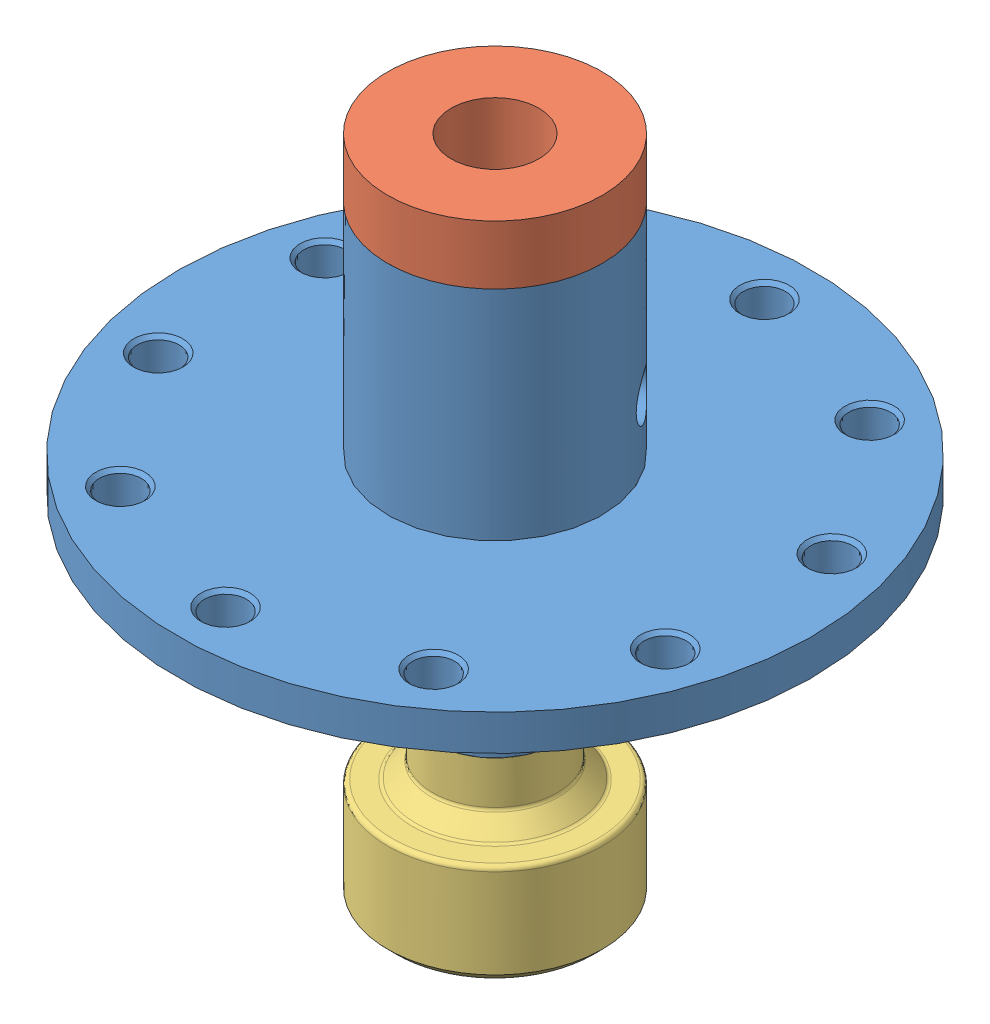
SolidWorks assembly 000012_R05_ASI_ASSEM, configuration Default. Lengths in mm.
Overall size (125.84 94.24 125.84).
3 component instances, 3 part files, 6 mates.
Components (placement in the parent):
- 000011-R07_ASI_TOP-1: 000011-R07_ASI_TOP [Default] x (0.583403 0 0.812183) z (-0.812183 0 0.583403) size (90.17 69.83 90.17)
- 000010-R02_ASI-1: 000010-R02_ASI [Default] at (0 25.4 0) x (-0.830204 0 0.55746) z (-0.55746 0 -0.830204) size (30.48 19.05 30.48)
- 000011-R04_ASI_BOTTOM-1: 000011-R04_ASI_BOTTOM [Default] at (0 -33.766 0) x (0.929472 0 0.368892) z (-0.368892 0 0.929472) size (30.48 23.65 30.48)
Mates (geometry in assembly coordinates):
- Concentric7: concentric aligned: circle of 000011-R07_ASI_TOP-1; line of assembly
- Coincident13: coincident: plane of 000011-R07_ASI_TOP-1 through (0 -33.766 0) normal (0 -1 0); line of assembly
- Concentric8: concentric aligned: cylinder of 000011-R07_ASI_TOP-1 through (0 9.944 0) axis (0 -1 0) radius 15.24; cylinder of 000010-R02_ASI-1 through (0 43.18 0) axis (0 -1 0) radius 12.065
- Coincident15: coincident anti-aligned: plane of 000011-R07_ASI_TOP-1 through (8.8911 36.068 12.3777) normal (0 1 0); plane of 000010-R02_ASI-1 through (0 36.068 0) normal (0 -1 0)
- Concentric9: concentric aligned: cylinder of 000011-R07_ASI_TOP-1 through (0 9.944 0) axis (0 -1 0) radius 7.62; cylinder of 000011-R04_ASI_BOTTOM-1 through (0 -1066.786 0) axis (0 -1 0) radius 8.89
- Coincident16: coincident anti-aligned: plane of 000011-R07_ASI_TOP-1 through (4.4455 -26.146 6.1888) normal (0 -1 0); plane of 000011-R04_ASI_BOTTOM-1 through (5.9022 -26.146 2.3425) normal (0 1 0)
